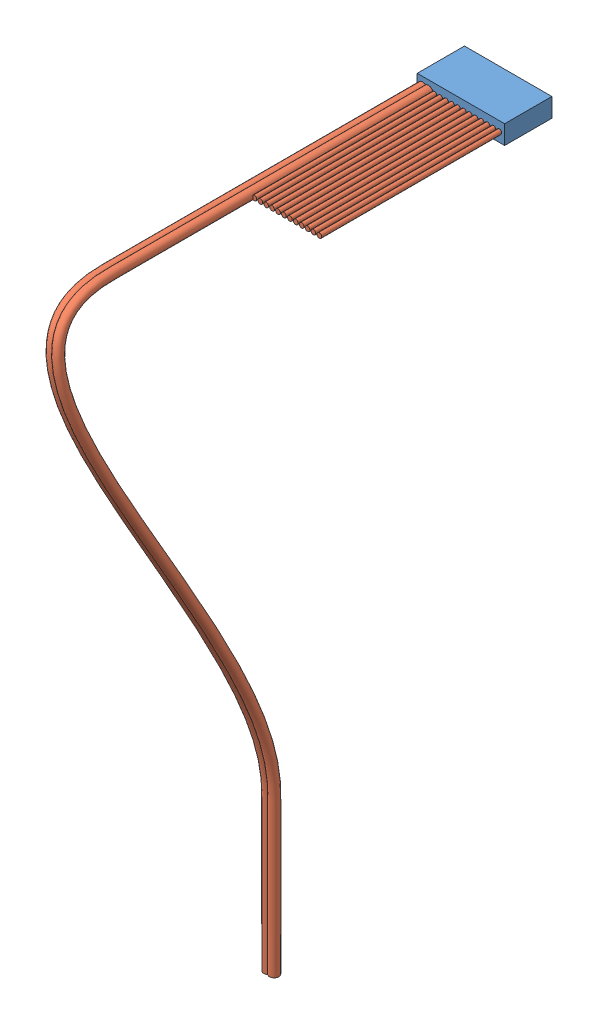
SolidWorks assembly Harness_1-CABLE_HARNESSING_ASSEMBLY, configuration Default. Lengths in mm.
Overall size (19.38 138.66 91.01).
4 component instances, 4 part files, 0 mates.
Components (placement in the parent):
- 14_PIN-1: 14_PIN [Default] at (-10.4388 134.7356 -150.4454) size (18.5 4 20)
- Cable^Harness_1-CABLE_HARNESSING_ASSEMBLY-1: Cable^Harness_1-CABLE_HARNESSING_ASSEMBLY [Default] at origin size (18.75 138.66 81.76) (virtual)
- Flattened_Cable^Harness_1-CABLE_HARNESSING_ASSEMBLY-1: Flattened_Cable^Harness_1-CABLE_HARNESSING_ASSEMBLY [Default] at origin (suppressed, hidden, virtual)
- Flattened_Cable_1^Harness_1-CABLE_HARNESSING_ASSEMBLY-1: Flattened_Cable_1^Harness_1-CABLE_HARNESSING_ASSEMBLY [Default] at origin (suppressed, hidden, virtual)
